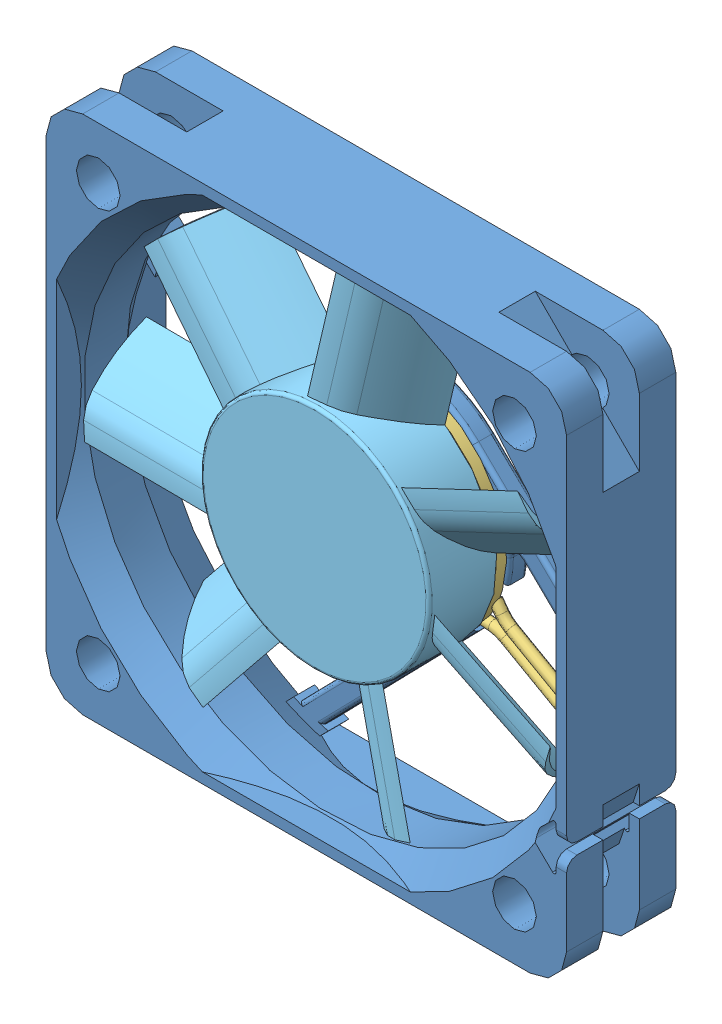
SolidWorks assembly Cooler 50x50x10.5 detailed SBORKA, configuration Default. Lengths in mm.
Overall size (56.44 55.29 12.93).
5 component instances, 5 part files, 9 mates.
Components (placement in the parent):
- Cooler 50x50x10.5 body-1: Cooler 50x50x10.5 body [Default] at (41.3687 25.409 14.5896) size (50 50 12.93)
- Sticker SUNON-1: Sticker SUNON [Default] at (41.3687 25.409 14.5896) x (-1 0 0) z (0 0 -1) size (18 18 0.07)
- Cooler pcb-1: Cooler pcb [Default] at (41.3687 25.409 17.5896) x (-0.870378 0.492384 0) z (0 0 -1) size (37.75 21.5 5.61)
- Cooler Motor-1: Cooler Motor [Default] at (41.3687 25.409 14.5896) x (0.999688 -0.024998 0) z (0 0 1) size (18 18 8.5)
- Cooler Blades-1: Cooler Blades [Default] at (41.3687 25.409 17.7896) x (-0.973565 0.228411 0) z (0 0 1) size (46 46 8.5)
Mates (geometry in assembly coordinates):
- Совпадение1: coincident anti-aligned: plane of Cooler 50x50x10.5 body-1 through (41.3687 25.409 16.5896) normal (0 0 1); plane of Cooler pcb-1 through (41.3687 25.409 16.5896) normal (0 0 -1)
- Концентричный1: concentric aligned: cylinder of Cooler 50x50x10.5 body-1 through (41.3687 25.409 25.0896) axis (0 0 -1) radius 2.75; cylinder of Cooler pcb-1 through (41.3687 25.409 17.5896) axis (0 0 -1) radius 3
- Совпадение2: coincident anti-aligned: plane of Cooler 50x50x10.5 body-1 through (62.8687 46.909 14.5896) normal (0 0 -1); plane of Sticker SUNON-1 through (41.3687 25.409 14.5896) normal (0 0 1)
- Параллельность1: parallel: plane of Cooler 50x50x10.5 body-1 through (19.8687 50.409 25.0896) normal (0 1 0); line of Sticker SUNON-1 through (32.5869 27.3787 14.5296) axis (1 0 0)
- Концентричный2: concentric anti-aligned: cylinder of Cooler 50x50x10.5 body-1 through (41.3687 25.409 25.0896) axis (0 0 -1) radius 2.75; cylinder of Sticker SUNON-1 through (41.3687 25.409 14.5396) axis (0 0 1) radius 9
- Концентричный3: concentric aligned: cylinder of Cooler 50x50x10.5 body-1 through (41.3687 25.409 25.0896) axis (0 0 -1) radius 2.75; cylinder of Cooler Motor-1 through (41.3687 25.409 17.5896) axis (0 0 -1) radius 2.75
- Совпадение4: coincident aligned: plane of Cooler 50x50x10.5 body-1 through (62.8687 46.909 14.5896) normal (0 0 -1); plane of Cooler Motor-1 through (41.3687 25.409 14.5896) normal (0 0 -1)
- Концентричный4: concentric aligned: cylinder of Cooler Blades-1 through (41.3687 25.409 15.7896) axis (0 0 1) radius 0.7; cylinder of Cooler Motor-1 through (41.3687 25.409 15.5896) axis (0 0 1) radius 0.75
- Расстояние1: distance = 0.8 mm aligned: plane of Cooler Blades-1 through (41.3687 25.409 24.2896) normal (0 0 1); plane of Cooler 50x50x10.5 body-1 through (62.8687 46.909 25.0896) normal (0 0 1)
